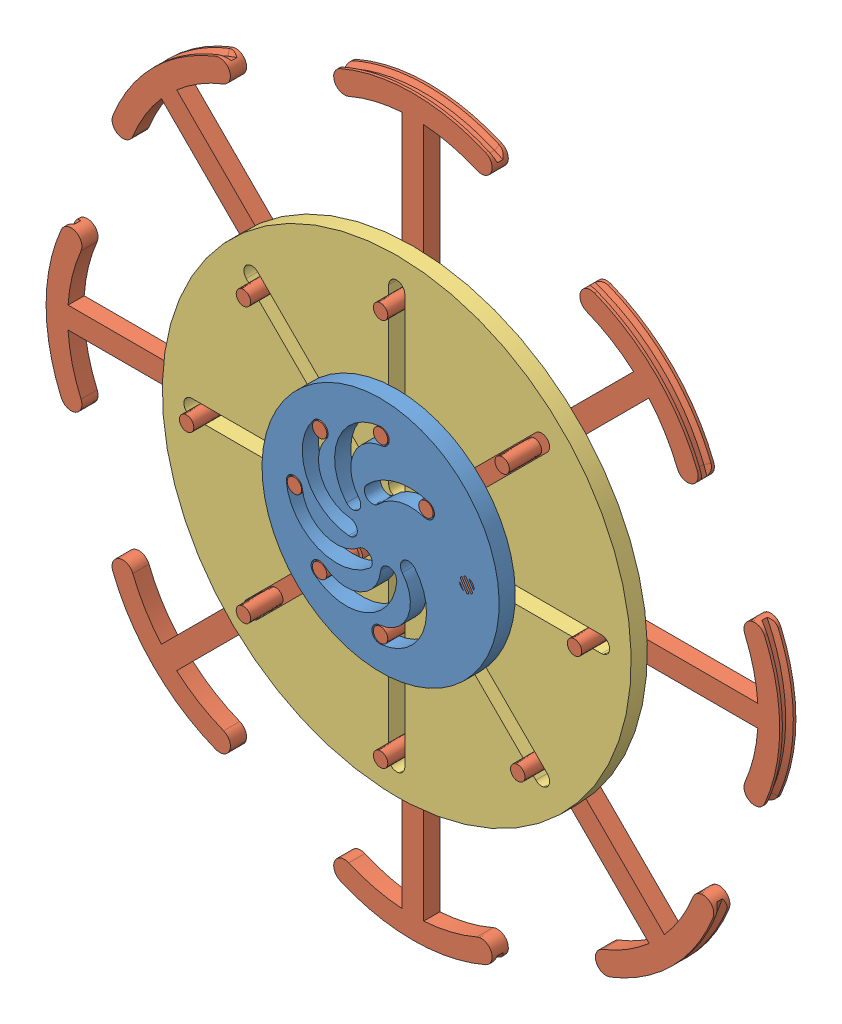
SolidWorks assembly asm_expanding-pulley-asymmetric, configuration Default. Lengths in mm.
Overall size (216.07 216.07 14.7).
11 component instances, 3 part files, 11 mates.
Components (placement in the parent):
- pulley-disc-asymmetric-1: pulley-disc-asymmetric [Default] at (0 -3.175 0) x (0.506097 0.862477 0) z (0 0 1) size (69.85 69.85 4.76)
- pulley-slider-1: pulley-slider [Default] at (0 22.2056 -9.525) size (46.69 85.83 14.7)
- pulley-slot-1: pulley-slot [Default] at (-5.08 1.27 -4.7625) x (1 0 0) z (0 -1 0) size (138.11 4.76 138.11)
- pulley-slider-3: pulley-slider [Default] at (-17.9468 14.7718 -9.525) x (0.707107 0.707107 0) z (0 0 1) size (46.69 85.83 14.7)
- pulley-slider-4: pulley-slider [Default] at (-25.3806 -3.175 -9.525) x (0 1 0) z (0 0 1) size (46.69 85.83 14.7)
- pulley-slider-5: pulley-slider [Default] at (-17.9468 -21.1218 -9.525) x (-0.707107 0.707107 0) z (0 0 1) size (46.69 85.83 14.7)
- pulley-slider-6: pulley-slider [Default] at (0 -28.5556 -9.525) x (-1 0 0) z (0 0 1) size (46.69 85.83 14.7)
- pulley-slider-7: pulley-slider [Default] at (17.9468 -21.1218 -9.525) x (-0.707107 -0.707107 0) z (0 0 1) size (46.69 85.83 14.7)
- pulley-slider-8: pulley-slider [Default] at (25.3806 -3.175 -9.525) x (0 -1 0) z (0 0 1) size (46.69 85.83 14.7)
- pulley-slider-9: pulley-slider [Default] at (17.9468 14.7718 -9.525) x (0.707107 -0.707107 0) z (0 0 1) size (46.69 85.83 14.7) (suppressed, hidden)
- pulley-slider-10: pulley-slider [Default] at (13.3605 10.1855 -9.525) x (0.707107 -0.707107 0) z (0 0 1) size (46.69 85.83 14.7)
Mates (geometry in assembly coordinates):
- Coincident1: coincident aligned: plane of pulley-disc-asymmetric-1 through (0 -3.175 4.7625) normal (0 0 1); plane of pulley-slider-1 through (0 22.2056 4.7625) normal (0 0 1)
- Slot1: slot aligned: cylinder of pulley-slider-1 through (0 22.2056 4.7625) axis (0 0 -1) radius 2.1272; cylinder of pulley-disc-asymmetric-1 through (1.3999 9.725 4.7625) axis (0 0 -1) radius 14.9401; cylinder of pulley-disc-asymmetric-1 through (-8.2151 1.6456 4.7625) axis (0 0 -1) radius 2.3813
- Parallel1: parallel anti-aligned: plane of pulley-disc-asymmetric-1 through (0 -3.175 0) normal (0 0 -1); plane of pulley-slot-1 through (0 -3.175 0) normal (0 0 1)
- Slot2: slot aligned: cylinder of pulley-slider-1 through (0 22.2056 4.7625) axis (0 0 -1) radius 2.1272; plane of pulley-slot-1 through (2.3813 6.35 0) normal (-1 0 0); cylinder of pulley-slot-1 through (0 6.35 0) axis (0 0 -1) radius 2.3813
- Coincident3: coincident aligned: line of pulley-disc-asymmetric-1 through (0 -3.175 0) axis (0 0 1); line of pulley-slot-1 through (0 -3.175 -4.7625) axis (0 0 1)
- Coincident4: coincident anti-aligned: plane of pulley-disc-asymmetric-1 through (0 -3.175 0) normal (0 0 -1); plane of pulley-slot-1 through (0 -3.175 0) normal (0 0 1)
- Slot3: slot aligned: cylinder of pulley-slider-1 through (0 53.9556 4.7625) axis (0 0 -1) radius 2.1272; plane of pulley-slot-1 through (2.3813 6.35 0) normal (-1 0 0); cylinder of pulley-slot-1 through (0 6.35 0) axis (0 0 -1) radius 2.3813
- Coincident5: coincident aligned: plane of pulley-slider-7 through (56.917 -88.6202 -4.7625) normal (0 0 1); plane of pulley-slider-10 through (80.8589 49.1557 -4.7625) normal (0 0 1)
- Slot4: slot aligned: cylinder of pulley-slider-10 through (13.3605 10.1855 4.7625) axis (0 0 -1) radius 2.1272; plane of pulley-slot-1 through (5.0514 5.244 0) normal (0.707107 -0.707107 0); cylinder of pulley-slot-1 through (42.6562 39.4812 0) axis (0 0 -1) radius 2.3813
- Slot5: slot aligned: cylinder of pulley-slider-10 through (13.3605 10.1855 4.7625) axis (0 0 -1) radius 2.1272; cylinder of pulley-disc-asymmetric-1 through (8.8074 -4.5439 4.7625) axis (0 0 -1) radius 13.0358; cylinder of pulley-disc-asymmetric-1 through (-2.4003 6.0426 4.7625) axis (0 0 -1) radius 2.3813
- Slot6: slot aligned: cylinder of pulley-slider-10 through (35.8111 32.6361 4.7625) axis (0 0 -1) radius 2.1272; plane of pulley-slot-1 through (5.0514 5.244 0) normal (0.707107 -0.707107 0); cylinder of pulley-slot-1 through (42.6562 39.4812 0) axis (0 0 -1) radius 2.3813
